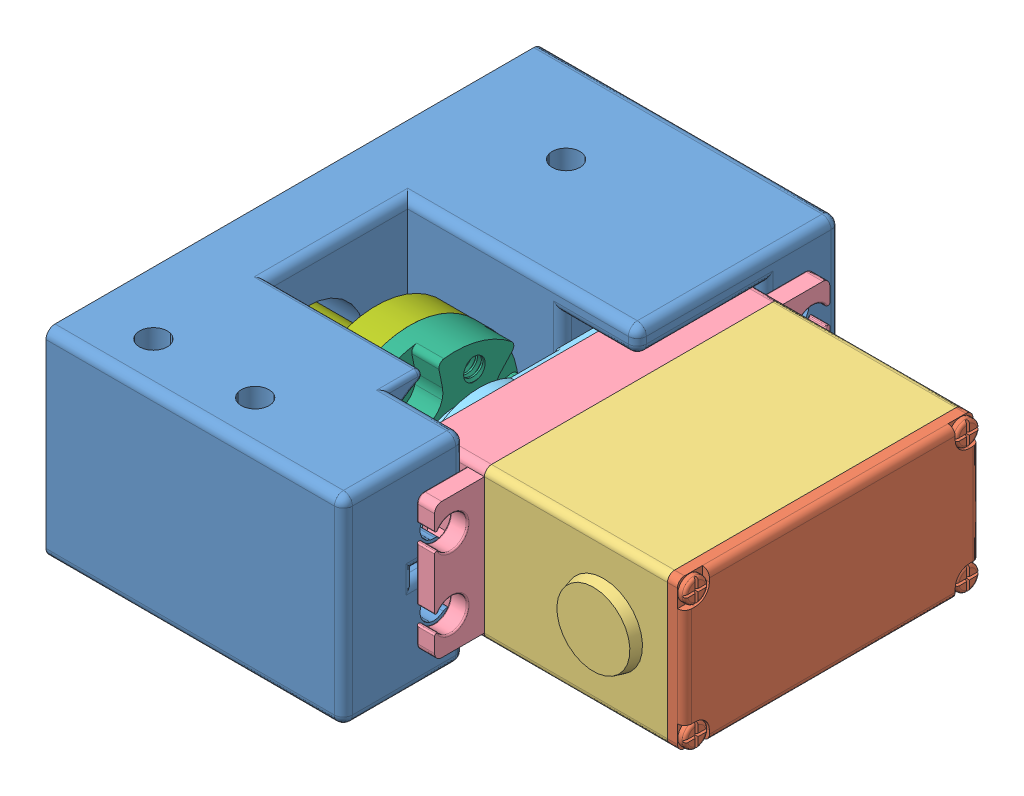
SolidWorks assembly MS-SA-0013a-03-Hand Servo Mount Assembly, configuration Default. Lengths in mm.
Overall size (72.39 31.33 69.75).
8 component instances, 7 part files, 8 mates.
Components (placement in the parent):
- MS-P-0055-03 Hand Servo Mount-1: MS-P-0055-03 Hand Servo Mount [Default] at (12.5808 33.9393 61.1705) size (41.76 27.94 69.75)
- 11886-1: 11886 [Default] at (71.9223 31.717 49.4945) x (0 1 0) z (0 0 1) size (21 45.43 55.5)
  - 11886_bottom-1: 11886_bottom [Default] at (2.2223 -4.2785 0.9275) size (21 2.43 41.5)
  - 11886_middle-1: 11886_middle [Default] at (2.2223 -1.8785 0.9275) size (21 25.7 42.9)
  - 11886_upper-1: 11886_upper [Default] at (6.1473 23.8215 -5.3225) size (21 8.72 55.5)
  - 11886_top-1: 11886_top [Default] at (2.2223 32.5215 0.7275) size (20 8.6 36.5)
- MS-C-0027-Servo Horn-1: MS-C-0027-Servo Horn [Default] at (34.0008 33.9393 61.172) x (0 0.962595 -0.270945) z (0 0.270945 0.962595) size (25.39 6.35 25.39)
- MS-P-0060-03-Hand Servo Pulley-1: MS-P-0060-03-Hand Servo Pulley [Default] at (22.8883 33.9393 61.172) x (0 0.270945 0.962595) z (0 -0.962595 0.270945) size (25.4 23.81 25.4)
Mates (geometry in assembly coordinates):
- Concentric1: concentric aligned: circle of MS-P-0055-03 Hand Servo Mount-1; circle of 11886-1/11886_upper-1
- Coincident1: coincident anti-aligned: plane of MS-P-0055-03 Hand Servo Mount-1 through (45.6008 33.9393 61.1705) normal (1 0 0); plane of 11886-1/11886_upper-1 through (45.6008 16.8334 22.672) normal (-1 0 0)
- Parallel1: parallel aligned: plane of MS-P-0055-03 Hand Servo Mount-1 through (-71.2981 47.9093 61.1705) normal (0 1 0); plane of 11886-1/11886_middle-1 through (48.1008 44.4393 71.172) normal (0 1 0)
- Concentric6: concentric anti-aligned: circle of 11886-1/11886_top-1; circle of MS-C-0027-Servo Horn-1
- Coincident3: coincident anti-aligned: plane of 11886-1/11886_top-1 through (34.0008 33.9393 61.172) normal (-1 0 0); plane of MS-C-0027-Servo Horn-1 through (34.0008 33.9393 61.172) normal (1 0 0)
- Concentric7: concentric aligned: circle of MS-C-0027-Servo Horn-1; circle of MS-P-0060-03-Hand Servo Pulley-1
- Concentric8: concentric aligned: circle of MS-C-0027-Servo Horn-1; circle of MS-P-0060-03-Hand Servo Pulley-1
- Coincident4: coincident anti-aligned: plane of MS-C-0027-Servo Horn-1 through (27.6508 33.9393 61.172) normal (-1 0 0); plane of MS-P-0060-03-Hand Servo Pulley-1 through (27.6508 33.9393 61.172) normal (1 0 0)
